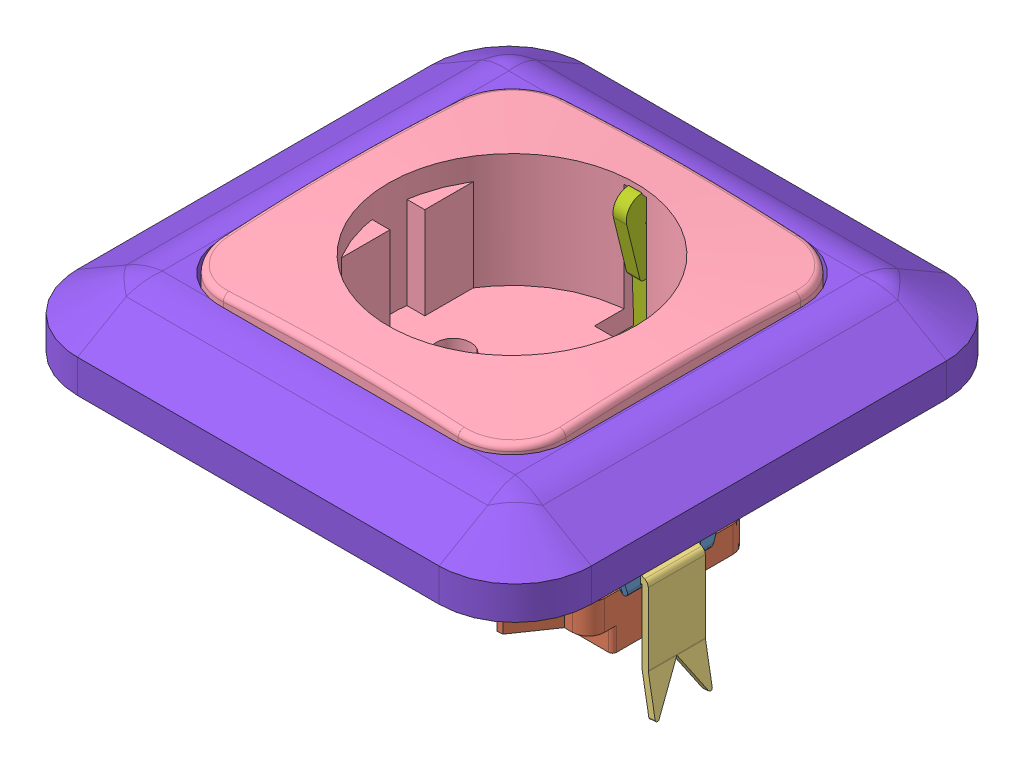
SolidWorks assembly Steckdose_1er, configuration Standard. Lengths in mm.
Overall size (81 48.85 80).
10 component instances, 8 part files, 3 mates.
Components (placement in the parent):
- Steckdose-1: Steckdose [Standard] at (48.5208 13.0547 -6.2011) size (71 48.85 71)
  - Montageplatte.02-1: Montageplatte.02 [Standard] at (-129.6803 11 128.1202) x (1 0 0) z (0 1 0) size (71 71 18.97)
  - Halter-1: Halter [Standard] at (-129.6803 11 128.1202) x (1 0 0) z (0 1 0) size (45.97 31.9 15.37)
  - Kralle.04-1: Kralle.04 [Standard] at (-126.9942 12.4168 128.1202) x (0.996195 -0.087156 0) z (0.087156 0.996195 0) size (8.78 9 23.36)
  - Kralle.04-2: Kralle.04 [Standard] at (21.6299 12.4168 26.282) x (-0.996195 -0.087156 0) z (-0.087156 0.996195 0) size (8.78 9 23.36)
  - Buchse-1: Buchse [Standard] at (-129.6803 10.7714 128.1202) x (1 0 0) z (0 1 0) size (64.03 64.03 27)
  - Stromklemme_1.02-1: Stromklemme_1.02 [Standard] at (-129.6803 11 127.9932) x (1 0 0) z (0 1 0) size (8.38 19.82 12.51)
  - Stromklemme_2.02-1: Stromklemme_2.02 [Standard] at (-129.6803 11 127.9932) x (1 0 0) z (0 1 0) size (8.38 19.82 12.51)
  - Erdleiter-1: Erdleiter [Standard] at (-129.6803 11 128.1202) x (1 0 0) z (0 1 0) size (7.24 44.01 27.12)
- Wandplatte_1er-1: Wandplatte_1er [Standard] at (-10.1594 23.8261 121.9191) x (1 0 0) z (0 1 0) size (81 80 11.01)
Mates (geometry in assembly coordinates):
- Abstand2: distance = 0.5 mm anti-aligned: plane of Steckdose-1/Buchse-1 through (14.3387 17.8261 98) normal (0 0 1); plane of Wandplatte_1er-1 through (-22.6613 17.8261 98.5) normal (0 0 -1)
- Abstand1: distance = 0.5 mm anti-aligned: plane of Steckdose-1/Buchse-1 through (-31.1613 17.8261 89.5) normal (-1 0 0); plane of Wandplatte_1er-1 through (-31.6613 17.8261 89.5) normal (1 0 0)
- Deckungsgleich3: coincident anti-aligned: plane of Steckdose-1/Buchse-1 through (-4.1613 17.8261 97.5) normal (0 -1 0); plane of Wandplatte_1er-1 through (-22.6613 17.8261 89) normal (0 1 0)
